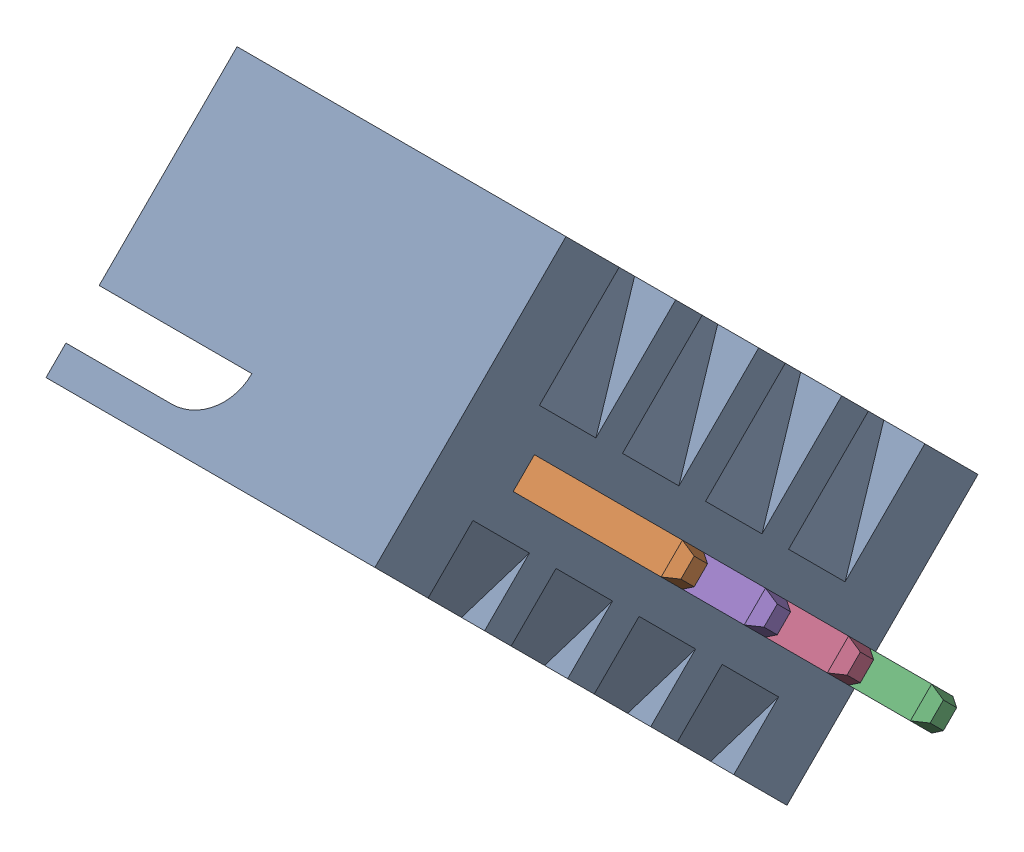
SolidWorks assembly JST-XH-4POS-VERT (1), configuration Default. Lengths in mm.
Overall size (10.4 12.83 12.83).
5 component instances, 2 part files, 0 mates.
Components (placement in the parent):
- Plastic (1)-1: Plastic (1) [Default] at (-6.1146 -33.6358 -52.1967) x (0 0.707107 0.707107) z (-1 0 0) size (12.4 5.75 7)
- Pin (1)-1: Pin (1) [Default] at (-7.7146 -29.3225 -51.2067) x (0 0.707107 0.707107) z (-1 0 0) size (0.64 0.64 10)
- Pin (1)-2: Pin (1) [Default] at (-7.7146 -34.6258 -56.51) x (0 0.707107 0.707107) z (-1 0 0) size (0.64 0.64 10)
- Pin (1)-3: Pin (1) [Default] at (-7.7146 -32.858 -54.7423) x (0 0.707107 0.707107) z (-1 0 0) size (0.64 0.64 10)
- Pin (1)-4: Pin (1) [Default] at (-7.7146 -31.0902 -52.9745) x (0 0.707107 0.707107) z (-1 0 0) size (0.64 0.64 10)
